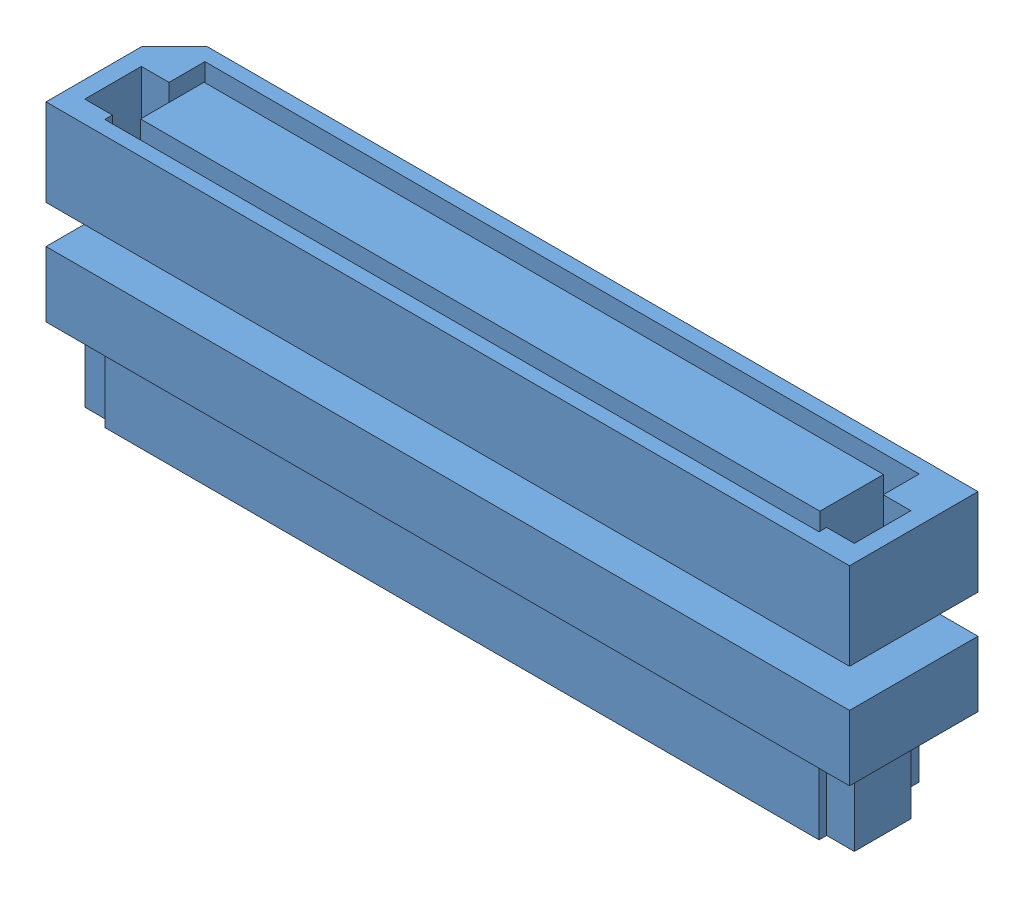
SolidWorks assembly FX8C-board-to-board-interconnects, configuration 100 without SV2 on bottom, but SV5 on top. Lengths in mm.
Overall size (94.9 9 81.4).
3 component instances, 1 part files, 0 mates.
Components (placement in the parent):
- FX8C-board-to-board-interconnects-1: FX8C-board-to-board-interconnects [100 without SV2 on bottom, but SV5 on top] at (26 0 -8) size (36.9 9 5.9)
- FX8C-board-to-board-interconnects-4: FX8C-board-to-board-interconnects [100 without SV2 on bottom, but SV5 on top] at (84 0 -8) size (36.9 9 5.9)
- FX8C-board-to-board-interconnects-3: FX8C-board-to-board-interconnects [100 without SV2 on bottom, but SV5 on top] at (55 0 -68) x (0 0 -1) z (1 0 0) size (36.9 9 5.9)
